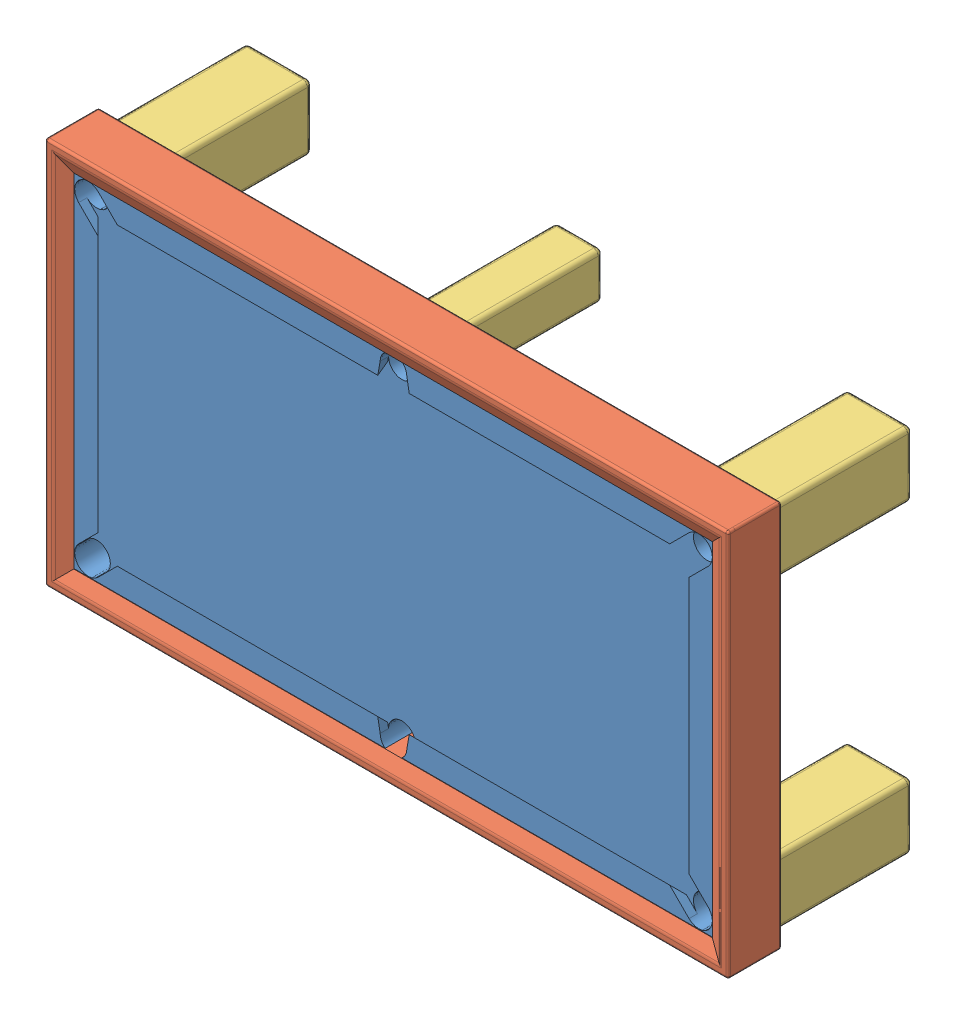
SolidWorks assembly Złożenie1, configuration Domyślna. Lengths in mm.
Overall size (2936 1666 830).
3 component instances, 3 part files, 0 mates.
Components (placement in the parent):
- PoolTableModel-1: PoolTableModel [Domyślna] at (-66.2478 -0.1269 357) size (2840 1570 786)
- Część1-1: Część1 [Domyślna] at origin size (2936 1666 230)
- Część2-1: Część2 [Domyślna] at origin size (2860 1590 600)
